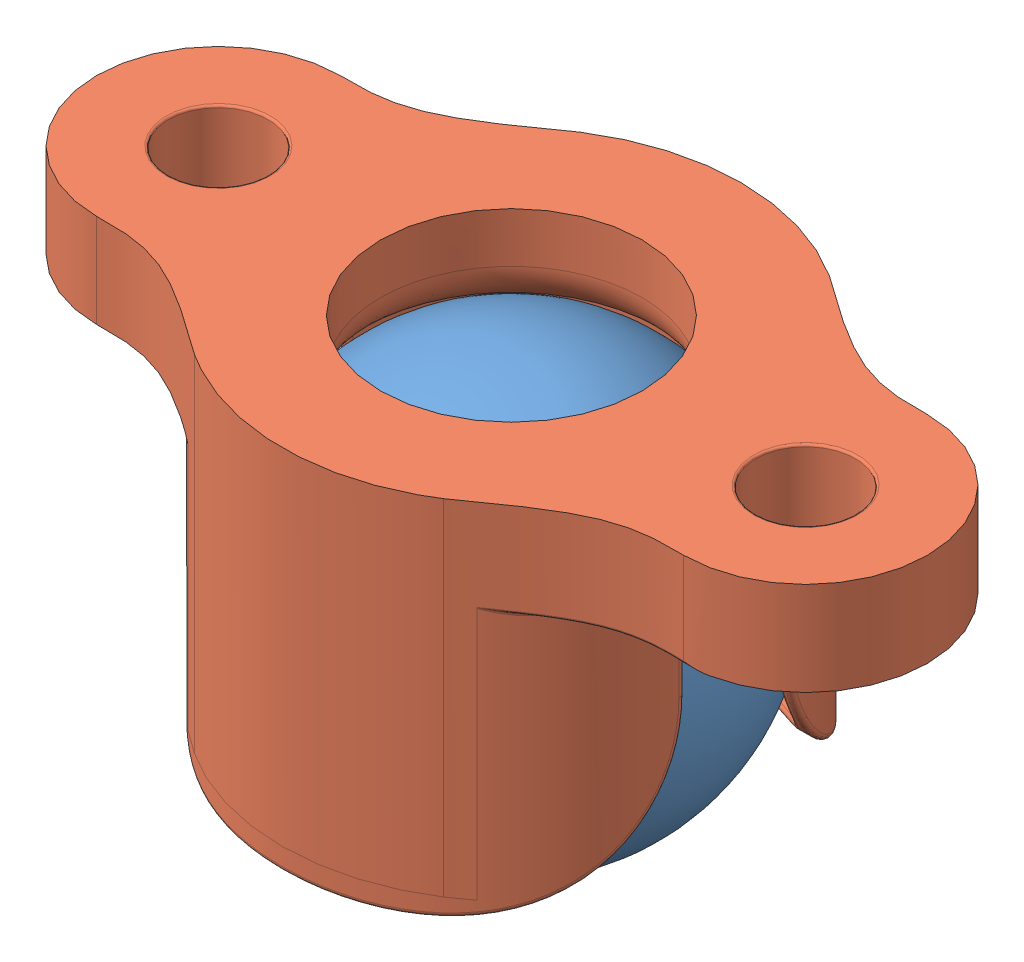
SolidWorks assembly Pololu Ball Caster with 38 Metal Ball, configuration Predeterminado. Lengths in mm.
Overall size (19.05 10.15 10.85).
2 component instances, 2 part files, 2 mates.
Components (placement in the parent):
- Pololu Ball Caster with 38 Metal Ballc-3: Pololu Ball Caster with 38 Metal Ballc [Predeterminado] at (-1.7621 0.4288 0.4956) size (9.53 9.53 9.53)
- Pololu Ball Caster with 38 Metal Balla-2: Pololu Ball Caster with 38 Metal Balla [Predeterminado] at (-2.2072 4.6726 1.1366) x (-1 0 0) z (0 0 1) size (19.05 8.71 10.85)
Mates (geometry in assembly coordinates):
- Concéntrica4: concentric: sphere of Pololu Ball Caster with 38 Metal Ballc-3; cylinder of Pololu Ball Caster with 38 Metal Balla-2 through (-1.7621 -2.0881 0.4956) axis (0 1 0) radius 5
- Concéntrica7: concentric: sphere of Pololu Ball Caster with 38 Metal Ballc-3; cylinder of Pololu Ball Caster with 38 Metal Balla-2 through (-1.7621 9.4333 0.4956) axis (0 -1 0) radius 3
